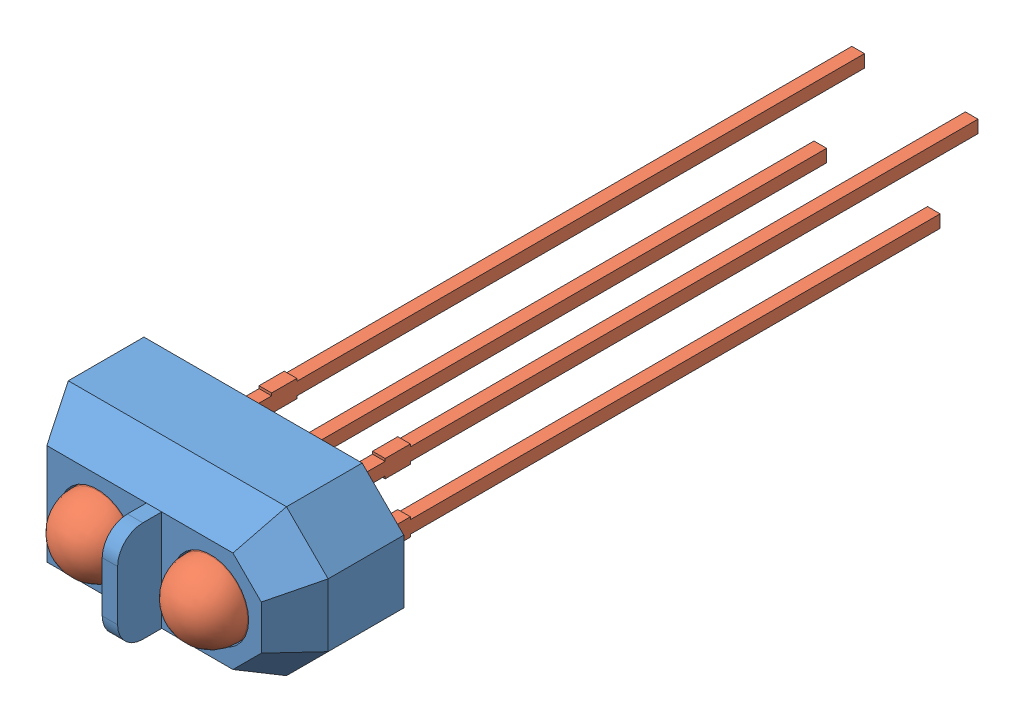
SolidWorks assembly User Library-TCRT-5000, configuration Default. Lengths in mm.
Overall size (10.3 5.8 10.55).
3 component instances, 2 part files, 0 mates.
Components (placement in the parent):
- User Library-TCRT-5000_Imported1-1: User Library-TCRT-5000_Imported1 [Default] at (2.9 2.9 0) size (10.3 5.8 6.5)
- User Library-TCRT-5000_Imported2-1: User Library-TCRT-5000_Imported2 [Default] at (0 0 1.5887) size (3.2 3.2 10.55)
- User Library-TCRT-5000_Imported2-2: User Library-TCRT-5000_Imported2 [Default] at (-4.5 0 1.5887) size (3.2 3.2 10.55)
